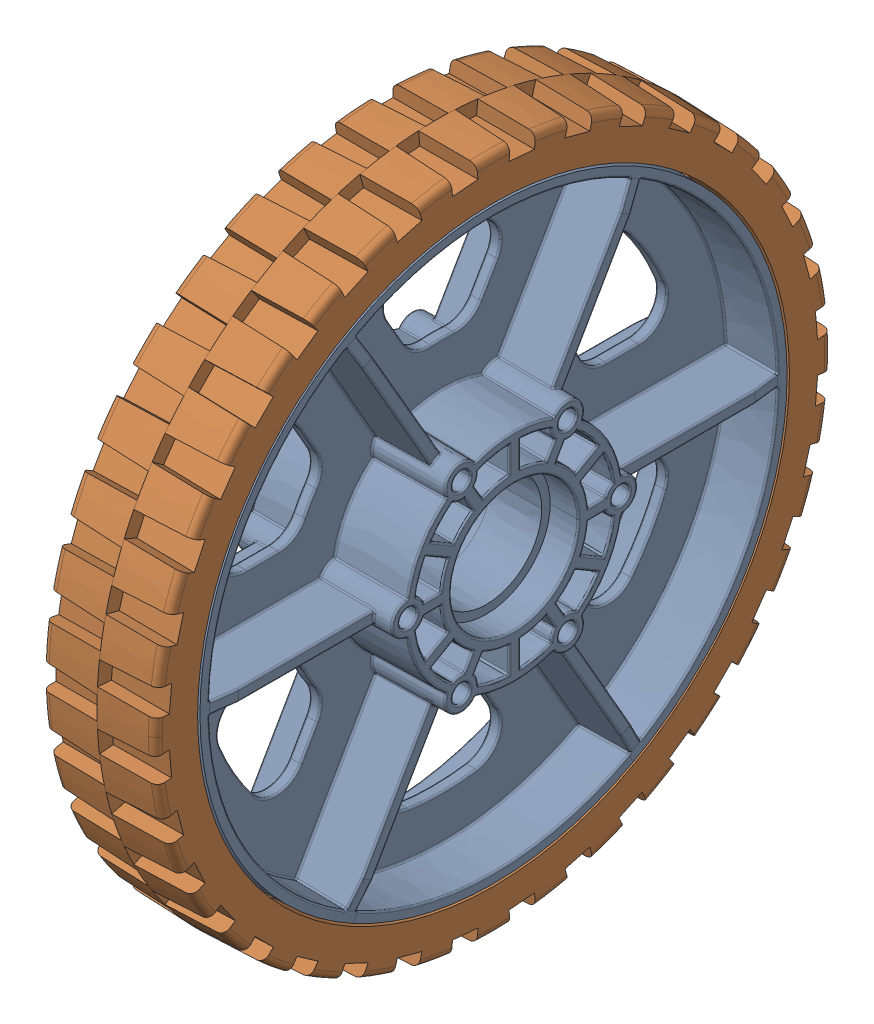
SolidWorks assembly 6 HiGrip Asm Rev II_80A, configuration Default. Lengths in mm.
Overall size (34.94 152.4 152.4).
2 component instances, 2 part files, 0 mates.
Components (placement in the parent):
- 6 wheel Rev 4-1: 6 wheel Rev 4 [Default] at (-52.6446 9.4231 21.378) size (34.94 132.08 132.08)
- 6 wheel tread II_80A-1: 6 wheel tread II_80A [Default] at (-65.3446 9.4231 21.378) x (0 0 -1) z (1 0 0) size (152.4 152.4 25.61)
